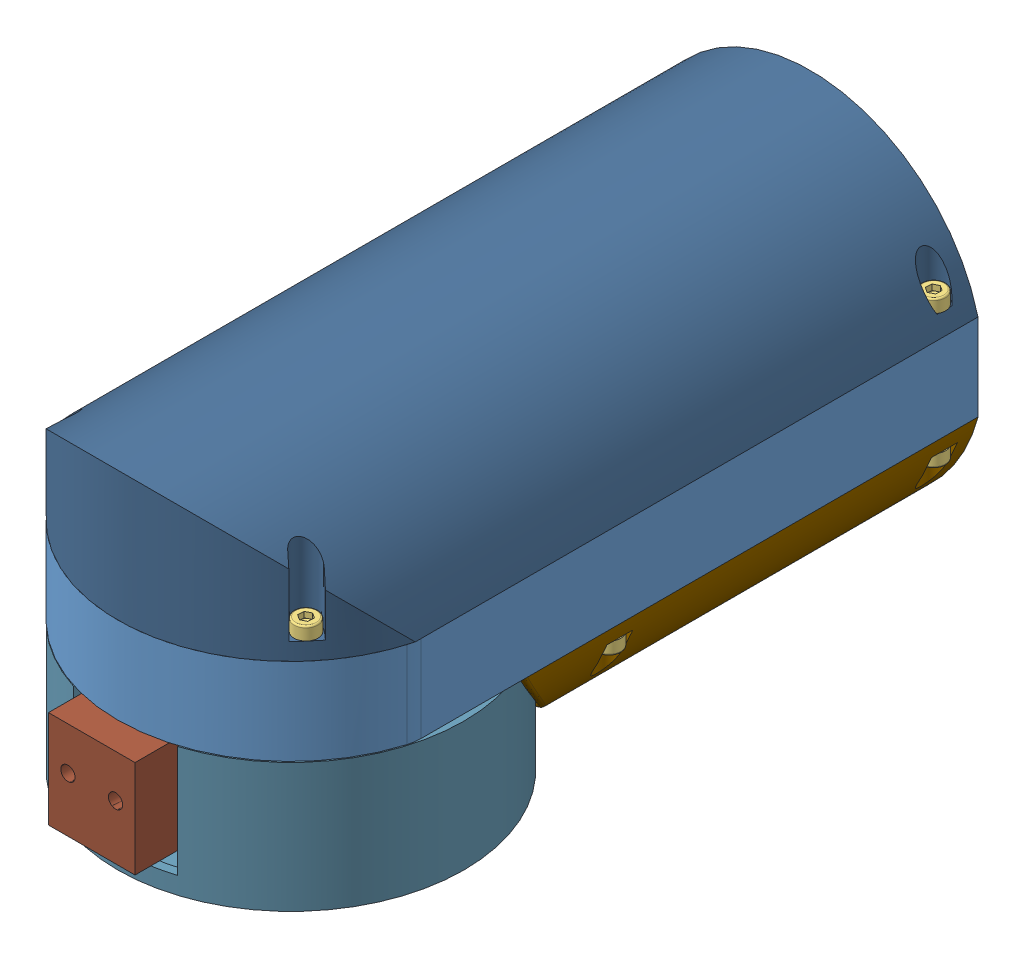
SolidWorks assembly 第四节, configuration 默认. Lengths in mm.
Overall size (92.23 82.42 236.24).
46 component instances, 16 part files, 78 mates.
Components (placement in the parent):
- 90003001-J4轴中间部件-1: 90003001-J4轴中间部件 [默认] at origin size (92.23 20 236.24)
- 90003005-HPG-11-45-1: 90003005-HPG-11-45 [默认] at (0 -28 190) x (1 0 0) z (0 1 0) size (40 40 65)
- hexagon socket head cap screws gb-1: hexagon socket head cap screws gb [GB_FASTENER_SCREWS_HSHCS M3X20-N] at (16.2635 -16 206.2635) x (0 1 0) z (0 0 1) size (23 5.5 5.5)
- hexagon socket head cap screws gb-2: hexagon socket head cap screws gb [GB_FASTENER_SCREWS_HSHCS M3X20-N] at (-16.2635 -16 206.2635) x (0 1 0) z (-1 0 0) size (23 5.5 5.5)
- hexagon socket head cap screws gb-3: hexagon socket head cap screws gb [GB_FASTENER_SCREWS_HSHCS M3X20-N] at (-16.2635 -16 173.7365) x (0 1 0) z (0 0 -1) size (23 5.5 5.5)
- hexagon socket head cap screws gb-4: hexagon socket head cap screws gb [GB_FASTENER_SCREWS_HSHCS M3X20-N] at (16.2635 -16 173.7365) x (0 1 0) z (1 0 0) size (23 5.5 5.5)
- 90000005-J1轴电机安装板-1: 90000005-J1轴电机安装板 [默认] at (0 12.2 125.5) x (1 0 0) z (0 -1 0) size (70 42 2.2)
- 90000015-汉德宝1701HS06AX-1: 90000015-汉德宝1701HS06AX [默认] at (0 -21 125.5) x (1 0 0) z (0 1 0) size (42.3 42.3 55)
- 90000014-BXR-020-10E抱闸-1: 90000014-BXR-020-10E抱闸 [默认] at (0 12.2 125.5) x (0.866025 0 -0.5) z (0 1 0) size (32 32 14)
- 90000007-3GT-24齿-6同步带轮-1: 90000007-3GT-24齿-6同步带轮 [默认] at (-0.2918 28.4 125.3475) x (0 0 -1) z (0 1 0) size (29.8 29.8 8)
- hex socket set screws with flat point gb-1: hex socket set screws with flat point gb [GB_FASTENER_SCREWS_HSFP M4X5-N] at (-7 30.4 125.5) size (5 4 4)
- hexagon socket head cap screws gb-5: hexagon socket head cap screws gb [GB_FASTENER_SCREWS_HSHCS M3X8-N] at (-32 15.2 110) x (0 -1 0) z (0 0 1) size (11 5.5 5.5)
- hexagon socket head cap screws gb-6: hexagon socket head cap screws gb [GB_FASTENER_SCREWS_HSHCS M3X8-N] at (-32 15.2 141) x (0 -1 0) z (0.972603 0 0.232473) size (11 5.5 5.5)
- hexagon socket head cap screws gb-7: hexagon socket head cap screws gb [GB_FASTENER_SCREWS_HSHCS M3X8-N] at (32 15.2 141) x (0 -1 0) z (0 0 1) size (11 5.5 5.5)
- hexagon socket head cap screws gb-8: hexagon socket head cap screws gb [GB_FASTENER_SCREWS_HSHCS M3X8-N] at (32 15.2 110) x (0 -1 0) z (0 0 1) size (11 5.5 5.5)
- hexagon socket head cap screws gb-9: hexagon socket head cap screws gb [GB_FASTENER_SCREWS_HSHCS M3X8-N] at (15.5 15.2 110) x (0 -1 0) z (0 0 1) size (11 5.5 5.5)
- 90003003-J4轴中间部件左端盖-1: 90003003-J4轴中间部件左端盖 [默认] at (0 0 230) x (1 0 0) z (0 0 -1) size (80 35.98 107.59)
- 90003002-J4轴中间部件右端盖-1: 90003002-J4轴中间部件右端盖 [默认] at (0 0 230) x (-1 0 0) z (0 0 -1) size (77.46 30 160)
- hexagon socket head cap screws gb-13: hexagon socket head cap screws gb [GB_FASTENER_SCREWS_HSHCS M3X8-N] at (-35 -17 76.5) x (0 1 0) z (1 0 0) size (11 5.5 5.5)
- hexagon socket head cap screws gb-14: hexagon socket head cap screws gb [GB_FASTENER_SCREWS_HSHCS M3X8-N] at (-35 17 76.5) x (0 -1 0) z (-0.837169 0 -0.546944) size (11 5.5 5.5)
- hexagon socket head cap screws gb-15: hexagon socket head cap screws gb [GB_FASTENER_SCREWS_HSHCS M3X8-N] at (35 17 76.5) x (0 -1 0) z (-0.837169 0 -0.546944) size (11 5.5 5.5)
- hexagon socket head cap screws gb-16: hexagon socket head cap screws gb [GB_FASTENER_SCREWS_HSHCS M3X8-N] at (35 -17 76.5) x (0 1 0) z (1 0 0) size (11 5.5 5.5)
- hexagon socket head cap screws gb-17: hexagon socket head cap screws gb [GB_FASTENER_SCREWS_HSHCS M3X8-N] at (35 -17 151.5) x (0 1 0) z (1 0 0) size (11 5.5 5.5)
- hexagon socket head cap screws gb-18: hexagon socket head cap screws gb [GB_FASTENER_SCREWS_HSHCS M3X8-N] at (-35 -17 151.5) x (0 1 0) z (1 0 0) size (11 5.5 5.5)
- hexagon socket head cap screws gb-19: hexagon socket head cap screws gb [GB_FASTENER_SCREWS_HSHCS M3X8-N] at (-28 17 214.5) x (0 -1 0) z (-0.837169 0 -0.546944) size (11 5.5 5.5)
- hexagon socket head cap screws gb-20: hexagon socket head cap screws gb [GB_FASTENER_SCREWS_HSHCS M3X8-N] at (28 17 214.5) x (0 -1 0) z (-0.837169 0 -0.546944) size (11 5.5 5.5)
- hex socket set screws with flat point gb-2: hex socket set screws with flat point gb [GB_FASTENER_SCREWS_HSFP M4X5-N] at (0 30.4 117.9297) x (0 0 1) z (-0.996976 0.077716 0) size (5 4 4)
- 90003006-J4轴转接法兰-1: 90003006-J4轴转接法兰 [默认] at (0 0 150) x (0 1 0) z (0 0 1) size (22.5 64 78)
- hexagon socket head cap screws gb-21: hexagon socket head cap screws gb [GB_FASTENER_SCREWS_HSHCS M3X12-N] at (0 -36 199) x (0 1 0) z (-0.668193 0 0.743988) size (15 5.5 5.5)
- hexagon socket head cap screws gb-22: hexagon socket head cap screws gb [GB_FASTENER_SCREWS_HSHCS M3X12-N] at (7.7942 -36 185.5) x (0 1 0) z (0.978409 0 0.206679) size (15 5.5 5.5)
- hexagon socket head cap screws gb-23: hexagon socket head cap screws gb [GB_FASTENER_SCREWS_HSHCS M3X12-N] at (-7.7942 -36 185.5) x (0 1 0) z (-0.310216 0 -0.950666) size (15 5.5 5.5)
- 90003008-3GT-24齿-6同步带轮行星端-1: 90003008-3GT-24齿-6同步带轮行星端 [默认] at (0 32.4 190) x (-1 0 0) z (0 -1 0) size (29.8 29.8 8)
- hex socket set screws with flat point gb-3: hex socket set screws with flat point gb [GB_FASTENER_SCREWS_HSFP M4X5-N] at (0 30.4 181.6) x (0 0 1) z (-0.234721 0.972063 0) size (5 4 4)
- 90003004-3GT-219-6-1: 90003004-3GT-219-6 [默认] at (-0.2918 33.4 189.8475) x (0 0 -1) z (0 -1 0) size (95.3 30.8 6)
- 90003009-J4轴转接法兰端盖-1: 90003009-J4轴转接法兰端盖 [默认] at (0 -40 190) x (-1 0 0) z (0 0 -1) size (80 29.8 80)
- hexagon socket head cap screws gb-24: hexagon socket head cap screws gb [GB_FASTENER_SCREWS_HSHCS M3X8-N] at (23 -40 190) x (0 1 0) z (1 0 0) size (11 5.5 5.5)
- hexagon socket head cap screws gb-25: hexagon socket head cap screws gb [GB_FASTENER_SCREWS_HSHCS M3X8-N] at (0 -40 213) x (0 1 0) z (0 0 1) size (11 5.5 5.5)
- hexagon socket head cap screws gb-26: hexagon socket head cap screws gb [GB_FASTENER_SCREWS_HSHCS M3X8-N] at (-23 -40 190) x (0 1 0) z (-1 0 0) size (11 5.5 5.5)
- hexagon socket head cap screws gb-27: hexagon socket head cap screws gb [GB_FASTENER_SCREWS_HSHCS M3X8-N] at (0 -40 167) x (0 1 0) z (0 0 -1) size (11 5.5 5.5)
- hexagon socket head cap screws gb-28: hexagon socket head cap screws gb [GB_FASTENER_SCREWS_HSHCS M4X20-N] at (-20.4 -5.5 84) x (0 0 -1) z (1 0 0) size (24 7 7)
- hexagon socket head cap screws gb-29: hexagon socket head cap screws gb [GB_FASTENER_SCREWS_HSHCS M4X20-N] at (-20.4 5.5 84) x (0 0 -1) z (-1 0 0) size (24 7 7)
- 90000025-PCBboard安装柱-1: 90000025-PCBboard安装柱 [默认] at (-25.0837 0 85.5) x (-0.923728 -0.383049 0) z (0 0 -1) size (5 6 10)
- 90000025-PCBboard安装柱-2: 90000025-PCBboard安装柱 [默认] at (24.9163 0 85.5) x (-0.923728 -0.383049 0) z (0 0 -1) size (5 6 10)
- 90000026-PCBboard-1: 90000026-PCBboard [默认] at (-0.0837 0 85.5) size (65 70 5)
- hexagon socket head cap screws gb-30: hexagon socket head cap screws gb [GB_FASTENER_SCREWS_HSHCS M3X8-N] at (24.9163 0 93.5) x (0 0 -1) z (0.923728 0.383049 0) size (11 5.5 5.5)
- hexagon socket head cap screws gb-31: hexagon socket head cap screws gb [GB_FASTENER_SCREWS_HSHCS M3X8-N] at (-25.0837 0 93.5) x (0 0 -1) z (0.923728 0.383049 0) size (11 5.5 5.5)
Mates (geometry in assembly coordinates):
- 重合1: coincident aligned: plane of 90003001-J4轴中间部件-1 through (0 0 0) normal (0 0 1); plane of assembly through (0 0 0) normal (0 0 1)
- 重合2: coincident aligned: plane of 90003001-J4轴中间部件-1 through (0 0 0) normal (0 1 0); plane of assembly through (0 0 0) normal (0 1 0)
- 重合3: coincident aligned: plane of 90003001-J4轴中间部件-1 through (0 0 0) normal (1 0 0); plane of assembly through (0 0 0) normal (1 0 0)
- 同心1: concentric aligned: cylinder of 90003001-J4轴中间部件-1 through (0 220 190) axis (0 -1 0) radius 20; cylinder of 90003005-HPG-11-45-1 through (0 72 190) axis (0 -1 0) radius 20
- 同心2: concentric anti-aligned: cylinder of 90003001-J4轴中间部件-1 through (16.2635 -8 206.2635) axis (0 -1 0) radius 1.25; cylinder of 90003005-HPG-11-45-1 through (16.2635 -13 206.2635) axis (0 1 0) radius 1.7
- 重合5: coincident anti-aligned: plane of 90003001-J4轴中间部件-1 through (0 -8 0) normal (0 -1 0); plane of 90003005-HPG-11-45-1 through (0 -8 190) normal (0 1 0)
- 同心3: concentric anti-aligned: cylinder of 90003005-HPG-11-45-1 through (16.2635 -13 206.2635) axis (0 1 0) radius 1.7; cylinder of hexagon socket head cap screws gb-1 through (16.2635 7 206.2635) axis (0 -1 0) radius 1.5
- 重合6: coincident anti-aligned: plane of 90003005-HPG-11-45-1 through (0 -13 190) normal (0 -1 0); plane of hexagon socket head cap screws gb-1 through (16.2635 -13 206.2635) normal (0 1 0)
- 同心4: concentric aligned: cylinder of 90003001-J4轴中间部件-1 through (-32 10 141) axis (0 1 0) radius 1.25; cylinder of 90000005-J1轴电机安装板-1 through (-32 10 141) axis (0 1 0) radius 1.75
- 同心5: concentric aligned: cylinder of 90003001-J4轴中间部件-1 through (-32 10 110) axis (0 1 0) radius 1.25; cylinder of 90000005-J1轴电机安装板-1 through (-32 10 110) axis (0 1 0) radius 1.75
- 重合7: coincident anti-aligned: plane of 90003001-J4轴中间部件-1 through (-115 10 230) normal (0 1 0); plane of 90000005-J1轴电机安装板-1 through (0 10 125.5) normal (0 -1 0)
- 同心6: concentric anti-aligned: cylinder of 90000005-J1轴电机安装板-1 through (0 10 125.5) axis (0 1 0) radius 11.5; cylinder of 90000015-汉德宝1701HS06AX-1 through (0 34 125.5) axis (0 -1 0) radius 2.5
- 同心7: concentric anti-aligned: cylinder of 90000005-J1轴电机安装板-1 through (-15.5 20 141) axis (0 -1 0) radius 1.75; cylinder of 90000015-汉德宝1701HS06AX-1 through (-15.5 10 141) axis (0 1 0) radius 1.25
- 重合8: coincident anti-aligned: plane of 90000005-J1轴电机安装板-1 through (0 10 125.5) normal (0 -1 0); plane of 90000015-汉德宝1701HS06AX-1 through (0 10 125.5) normal (0 1 0)
- 重合11: coincident anti-aligned: plane of 90000015-汉德宝1701HS06AX-1 through (-2 13 130.5) normal (-1 0 0); plane of hex socket set screws with flat point gb-1 through (-2 30.4 125.5) normal (1 0 0)
- 同心13: concentric aligned: cylinder of 90000005-J1轴电机安装板-1 through (-32 10 110) axis (0 1 0) radius 1.75; cylinder of hexagon socket head cap screws gb-5 through (-32 4.2 110) axis (0 1 0) radius 1.5
- 重合12: coincident anti-aligned: plane of 90000005-J1轴电机安装板-1 through (0 12.2 125.5) normal (0 1 0); plane of hexagon socket head cap screws gb-5 through (-32 12.2 110) normal (0 -1 0)
- 同心14: concentric aligned: cylinder of 90003001-J4轴中间部件-1 through (-32 10 141) axis (0 1 0) radius 1.25; cylinder of hexagon socket head cap screws gb-6 through (-32 4.2 141) axis (0 1 0) radius 1.5
- 重合13: coincident anti-aligned: plane of 90000005-J1轴电机安装板-1 through (0 12.2 125.5) normal (0 1 0); plane of hexagon socket head cap screws gb-6 through (-32 12.2 141) normal (0 -1 0)
- 同心15: concentric aligned: cylinder of 90003001-J4轴中间部件-1 through (32 10 141) axis (0 1 0) radius 1.25; cylinder of hexagon socket head cap screws gb-7 through (32 4.2 141) axis (0 1 0) radius 1.5
- 重合14: coincident anti-aligned: plane of 90000005-J1轴电机安装板-1 through (0 12.2 125.5) normal (0 1 0); plane of hexagon socket head cap screws gb-7 through (32 12.2 141) normal (0 -1 0)
- 同心16: concentric aligned: cylinder of 90003001-J4轴中间部件-1 through (32 10 110) axis (0 1 0) radius 1.25; cylinder of hexagon socket head cap screws gb-8 through (32 4.2 110) axis (0 1 0) radius 1.5
- 重合15: coincident anti-aligned: plane of 90000005-J1轴电机安装板-1 through (0 12.2 125.5) normal (0 1 0); plane of hexagon socket head cap screws gb-8 through (32 12.2 110) normal (0 -1 0)
- 同心17: concentric aligned: cylinder of 90000015-汉德宝1701HS06AX-1 through (15.5 10 110) axis (0 1 0) radius 1.25; cylinder of hexagon socket head cap screws gb-9 through (15.5 4.2 110) axis (0 1 0) radius 1.5
- 重合16: coincident anti-aligned: plane of 90000005-J1轴电机安装板-1 through (0 12.2 125.5) normal (0 1 0); plane of hexagon socket head cap screws gb-9 through (15.5 12.2 110) normal (0 -1 0)
- 同心18: concentric anti-aligned: cylinder of 90003001-J4轴中间部件-1 through (-35 -10 76.5) axis (0 -1 0) radius 1.25; cylinder of 90003003-J4轴中间部件左端盖-1 through (-35 -60 76.5) axis (0 1 0) radius 1.7
- 同心19: concentric anti-aligned: cylinder of 90003001-J4轴中间部件-1 through (35 -10 76.5) axis (0 -1 0) radius 1.25; cylinder of 90003003-J4轴中间部件左端盖-1 through (35 -60 76.5) axis (0 1 0) radius 1.7
- 重合17: coincident anti-aligned: plane of 90003001-J4轴中间部件-1 through (-115 -10 230) normal (0 -1 0); plane of 90003003-J4轴中间部件左端盖-1 through (0 -10 230) normal (0 1 0)
- 同心21: concentric anti-aligned: cylinder of 90003001-J4轴中间部件-1 through (-35 10 76.5) axis (0 1 0) radius 1.25; cylinder of 90003002-J4轴中间部件右端盖-1 through (-35 110 76.5) axis (0 -1 0) radius 1.7
- 同心22: concentric anti-aligned: cylinder of 90003001-J4轴中间部件-1 through (35 10 76.5) axis (0 1 0) radius 1.25; cylinder of 90003002-J4轴中间部件右端盖-1 through (35 110 76.5) axis (0 -1 0) radius 1.7
- 重合18: coincident anti-aligned: plane of 90003001-J4轴中间部件-1 through (-115 10 230) normal (0 1 0); plane of 90003002-J4轴中间部件右端盖-1 through (0 10 230) normal (0 -1 0)
- 同心23: concentric anti-aligned: cylinder of 90003003-J4轴中间部件左端盖-1 through (-35 -60 76.5) axis (0 1 0) radius 1.7; cylinder of hexagon socket head cap screws gb-13 through (-35 -6 76.5) axis (0 -1 0) radius 1.5
- 重合19: coincident anti-aligned: plane of 90003003-J4轴中间部件左端盖-1 through (0 -14 230) normal (0 -1 0); plane of hexagon socket head cap screws gb-13 through (-35 -14 76.5) normal (0 1 0)
- 同心24: concentric anti-aligned: cylinder of 90003002-J4轴中间部件右端盖-1 through (-35 110 76.5) axis (0 -1 0) radius 1.7; cylinder of hexagon socket head cap screws gb-14 through (-35 6 76.5) axis (0 1 0) radius 1.5
- 重合20: coincident anti-aligned: plane of 90003002-J4轴中间部件右端盖-1 through (-35 14 76.5) normal (0 1 0); plane of hexagon socket head cap screws gb-14 through (-35 14 76.5) normal (0 -1 0)
- 同心25: concentric anti-aligned: cylinder of 90003002-J4轴中间部件右端盖-1 through (35 110 76.5) axis (0 -1 0) radius 1.7; cylinder of hexagon socket head cap screws gb-15 through (35 6 76.5) axis (0 1 0) radius 1.5
- 重合21: coincident anti-aligned: plane of 90003002-J4轴中间部件右端盖-1 through (35 14 76.5) normal (0 1 0); plane of hexagon socket head cap screws gb-15 through (35 14 76.5) normal (0 -1 0)
- 同心26: concentric anti-aligned: cylinder of 90003003-J4轴中间部件左端盖-1 through (35 -60 76.5) axis (0 1 0) radius 1.7; cylinder of hexagon socket head cap screws gb-16 through (35 -6 76.5) axis (0 -1 0) radius 1.5
- 重合22: coincident anti-aligned: plane of 90003003-J4轴中间部件左端盖-1 through (0 -14 230) normal (0 -1 0); plane of hexagon socket head cap screws gb-16 through (35 -14 76.5) normal (0 1 0)
- 同心27: concentric anti-aligned: cylinder of 90003003-J4轴中间部件左端盖-1 through (35 -60 151.5) axis (0 1 0) radius 1.7; cylinder of hexagon socket head cap screws gb-17 through (35 -6 151.5) axis (0 -1 0) radius 1.5
- 重合23: coincident anti-aligned: plane of 90003003-J4轴中间部件左端盖-1 through (0 -14 230) normal (0 -1 0); plane of hexagon socket head cap screws gb-17 through (35 -14 151.5) normal (0 1 0)
- 同心28: concentric anti-aligned: cylinder of 90003003-J4轴中间部件左端盖-1 through (-35 -60 151.5) axis (0 1 0) radius 1.7; cylinder of hexagon socket head cap screws gb-18 through (-35 -6 151.5) axis (0 -1 0) radius 1.5
- 重合24: coincident anti-aligned: plane of 90003003-J4轴中间部件左端盖-1 through (0 -14 230) normal (0 -1 0); plane of hexagon socket head cap screws gb-18 through (-35 -14 151.5) normal (0 1 0)
- 同心29: concentric anti-aligned: cylinder of 90003002-J4轴中间部件右端盖-1 through (-28 110 214.5) axis (0 -1 0) radius 1.7; cylinder of hexagon socket head cap screws gb-19 through (-28 6 214.5) axis (0 1 0) radius 1.5
- 重合25: coincident anti-aligned: plane of 90003002-J4轴中间部件右端盖-1 through (-28 14 214.5) normal (0 1 0); plane of hexagon socket head cap screws gb-19 through (-28 14 214.5) normal (0 -1 0)
- 同心30: concentric anti-aligned: cylinder of 90003002-J4轴中间部件右端盖-1 through (28 110 214.5) axis (0 -1 0) radius 1.7; cylinder of hexagon socket head cap screws gb-20 through (28 6 214.5) axis (0 1 0) radius 1.5
- 重合26: coincident anti-aligned: plane of 90003002-J4轴中间部件右端盖-1 through (28 14 214.5) normal (0 1 0); plane of hexagon socket head cap screws gb-20 through (28 14 214.5) normal (0 -1 0)
- 同心32: concentric anti-aligned: cylinder of 90003005-HPG-11-45-1 through (0 -13 190) axis (0 -1 0) radius 20; cylinder of 90003006-J4轴转接法兰-1 through (0 -27.5 190) axis (0 1 0) radius 20
- 同心33: concentric aligned: cylinder of 90003005-HPG-11-45-1 through (0 -28 199) axis (0 -1 0) radius 1.65; cylinder of 90003006-J4轴转接法兰-1 through (0 -23 199) axis (0 -1 0) radius 1.7
- 重合27: coincident anti-aligned: plane of 90003005-HPG-11-45-1 through (0 -28 190) normal (0 -1 0); plane of 90003006-J4轴转接法兰-1 through (0 -28 190) normal (0 1 0)
- 同心35: concentric aligned: cylinder of 90003006-J4轴转接法兰-1 through (0 -23 199) axis (0 -1 0) radius 1.7; cylinder of hexagon socket head cap screws gb-21 through (0 -21 199) axis (0 -1 0) radius 1.5
- 重合30: coincident anti-aligned: plane of 90003006-J4轴转接法兰-1 through (115 -33 150) normal (0 -1 0); plane of hexagon socket head cap screws gb-21 through (0 -33 199) normal (0 1 0)
- 重合34: coincident anti-aligned: plane of 90003005-HPG-11-45-1 through (0 -28 186.6) normal (0 0 -1); plane of hex socket set screws with flat point gb-3 through (0 30.4 186.6) normal (0 0 1)
- 同心36: concentric anti-aligned: cylinder of 90000015-汉德宝1701HS06AX-1 through (0 34 125.5) axis (0 -1 0) radius 2.5; cylinder of 90000014-BXR-020-10E抱闸-1 through (0 12.2 125.5) axis (0 1 0) radius 4.5
- 同心37: concentric anti-aligned: cylinder of 90000005-J1轴电机安装板-1 through (-7 10 137.6244) axis (0 -1 0) radius 1.25; cylinder of 90000014-BXR-020-10E抱闸-1 through (-7 12.2 137.6244) axis (0 1 0) radius 1.25
- 重合35: coincident anti-aligned: plane of 90000005-J1轴电机安装板-1 through (0 12.2 125.5) normal (0 1 0); plane of 90000014-BXR-020-10E抱闸-1 through (-5.9267 12.2 147.6187) normal (0 -1 0)
- 同心38: concentric aligned: cylinder of 90000007-3GT-24齿-6同步带轮-1 through (-0.2918 26.4 125.3475) axis (0 1 0) radius 14.9; cylinder of 90003004-3GT-219-6-1 through (-0.2918 27.4 125.3475) axis (0 1 0) radius 14.9
- 距离1: distance = 1 mm aligned: plane of 90000007-3GT-24齿-6同步带轮-1 through (-0.2918 26.4 125.3475) normal (0 -1 0); plane of 90003004-3GT-219-6-1 through (-0.2918 27.4 125.3475) normal (0 -1 0)
- 距离2: distance = 0.2 mm anti-aligned: plane of 90000007-3GT-24齿-6同步带轮-1 through (-0.2918 26.4 125.3475) normal (0 -1 0); plane of 90000014-BXR-020-10E抱闸-1 through (-5.9273 26.2 147.6177) normal (0 1 0)
- 同心42: concentric anti-aligned: cylinder of 90003006-J4轴转接法兰-1 through (0 -60.5 190) axis (0 1 0) radius 32; cylinder of 90003009-J4轴转接法兰端盖-1 through (0 -10 190) axis (0 -1 0) radius 38
- 平行1: parallel anti-aligned: plane of 90003006-J4轴转接法兰-1 through (10 -115 380) normal (1 0 0); plane of 90003009-J4轴转接法兰端盖-1 through (12 -36 238.9778) normal (-1 0 0)
- 同心43: concentric anti-aligned: cylinder of 90003009-J4轴转接法兰端盖-1 through (23 -83 190) axis (0 1 0) radius 1.7; cylinder of hexagon socket head cap screws gb-24 through (23 -29 190) axis (0 -1 0) radius 1.5
- 重合43: coincident anti-aligned: plane of 90003009-J4轴转接法兰端盖-1 through (23 -37 190) normal (0 -1 0); plane of hexagon socket head cap screws gb-24 through (23 -37 190) normal (0 1 0)
- 同心44: concentric aligned: circle of 90003001-J4轴中间部件-1; cylinder of hexagon socket head cap screws gb-28 through (-20.4 -5.5 60) axis (0 0 1) radius 2
- 重合44: coincident anti-aligned: plane of 90003001-J4轴中间部件-1 through (-32.5 15 80) normal (0 0 1); plane of hexagon socket head cap screws gb-28 through (-20.4 -5.5 80) normal (0 0 -1)
- 同心45: concentric anti-aligned: cylinder of 90003001-J4轴中间部件-1 through (-20.4 5.5 98) axis (0 0 -1) radius 2.25; cylinder of hexagon socket head cap screws gb-29 through (-20.4 5.5 60) axis (0 0 1) radius 2
- 重合45: coincident anti-aligned: plane of 90003001-J4轴中间部件-1 through (-32.5 15 80) normal (0 0 1); plane of hexagon socket head cap screws gb-29 through (-20.4 5.5 80) normal (0 0 -1)
- 同心46: concentric anti-aligned: cylinder of 90003001-J4轴中间部件-1 through (-25.0837 0 90) axis (0 0 1) radius 1.25; cylinder of 90000025-PCBboard安装柱-1 through (-25.0837 0 80) axis (0 0 -1) radius 1.5
- 重合46: coincident anti-aligned: plane of 90003001-J4轴中间部件-1 through (-32.5 15 80) normal (0 0 1); plane of 90000025-PCBboard安装柱-1 through (-25.0837 0 80) normal (0 0 -1)
- 同心47: concentric anti-aligned: cylinder of 90003001-J4轴中间部件-1 through (24.9163 0 90) axis (0 0 1) radius 1.25; cylinder of 90000025-PCBboard安装柱-2 through (24.9163 0 80) axis (0 0 -1) radius 1.5
- 重合47: coincident anti-aligned: plane of 90003001-J4轴中间部件-1 through (-32.5 15 80) normal (0 0 1); plane of 90000025-PCBboard安装柱-2 through (24.9163 0 80) normal (0 0 -1)
- 同心48: concentric aligned: cylinder of 90000025-PCBboard安装柱-1 through (-25.0837 0 85.5) axis (0 0 1) radius 1.25; cylinder of 90000026-PCBboard-1 through (-25.0837 0 80.5) axis (0 0 1) radius 1.7
- 同心49: concentric aligned: cylinder of 90000025-PCBboard安装柱-2 through (24.9163 0 85.5) axis (0 0 1) radius 1.25; cylinder of 90000026-PCBboard-1 through (24.9163 0 80.5) axis (0 0 1) radius 1.7
- 重合48: coincident anti-aligned: plane of 90000025-PCBboard安装柱-2 through (24.9163 0 85.5) normal (0 0 1); plane of 90000026-PCBboard-1 through (-0.0837 0 85.5) normal (0 0 -1)
- 同心50: concentric aligned: cylinder of 90000026-PCBboard-1 through (24.9163 0 80.5) axis (0 0 1) radius 1.7; cylinder of hexagon socket head cap screws gb-30 through (24.9163 0 82.5) axis (0 0 1) radius 1.5
- 重合49: coincident anti-aligned: plane of 90000026-PCBboard-1 through (-0.0837 0 90.5) normal (0 0 1); plane of hexagon socket head cap screws gb-30 through (24.9163 0 90.5) normal (0 0 -1)
- 同心51: concentric aligned: cylinder of 90000026-PCBboard-1 through (-25.0837 0 80.5) axis (0 0 1) radius 1.7; cylinder of hexagon socket head cap screws gb-31 through (-25.0837 0 82.5) axis (0 0 1) radius 1.5
- 重合50: coincident anti-aligned: plane of 90000026-PCBboard-1 through (-0.0837 0 90.5) normal (0 0 1); plane of hexagon socket head cap screws gb-31 through (-25.0837 0 90.5) normal (0 0 -1)
